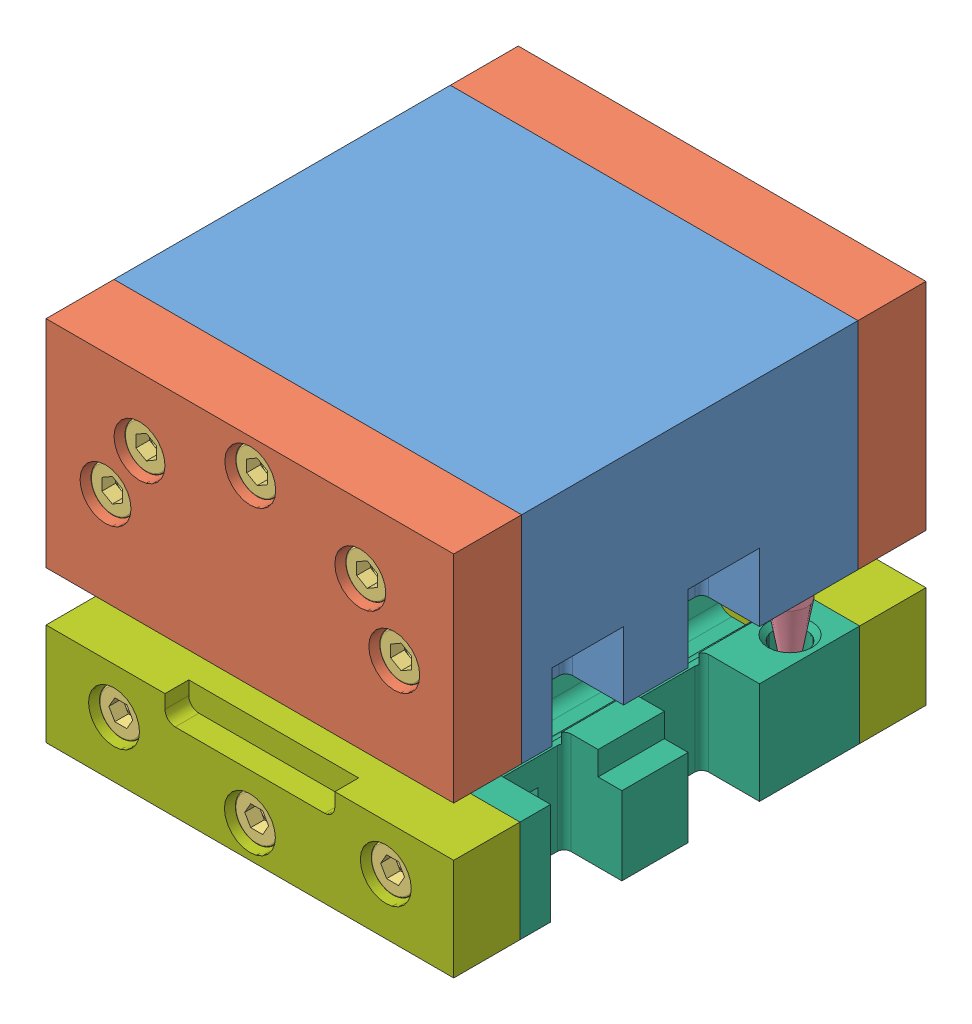
SolidWorks assembly Сборка, configuration По умолчанию. Lengths in mm.
Overall size (120 108.09 139).
27 component instances, 7 part files, 37 mates.
Components (placement in the parent):
- Матрица-1: Матрица [По умолчанию] at origin size (120 63.5 99)
- БоковинаПресс-формы-1: БоковинаПресс-формы [По умолчанию] at (0 63.5 0) x (0 0 -1) z (-1 0 0) size (20 63.5 120)
- БоковинаПресс-формы-2: БоковинаПресс-формы [По умолчанию] at (120 63.5 99) x (0 0 1) z (1 0 0) size (20 63.5 120)
- socket head cap screw_iso-1: socket head cap screw_iso [ISO 4762 M8 x 16 - 16N] at (17.5 27.5 117) x (0 0 -1) z (1 0 0) size (24 13 13)
- socket head cap screw_iso-2: socket head cap screw_iso [ISO 4762 M8 x 16 - 16N] at (27.5 43.5 117) x (0 0 -1) z (1 0 0) size (24 13 13)
- socket head cap screw_iso-3: socket head cap screw_iso [ISO 4762 M8 x 16 - 16N] at (60.109 53.5 117) x (0 0 -1) z (1 0 0) size (24 13 13)
- socket head cap screw_iso-4: socket head cap screw_iso [ISO 4762 M8 x 16 - 16N] at (92.5 43.5 117) x (0 0 -1) z (1 0 0) size (24 13 13)
- socket head cap screw_iso-5: socket head cap screw_iso [ISO 4762 M8 x 16 - 16N] at (102.5 27.5 117) x (0 0 -1) z (1 0 0) size (24 13 13)
- socket head cap screw_iso-6: socket head cap screw_iso [ISO 4762 M8 x 16 - 16N] at (102.5 27.5 -18) x (0 0 1) z (-1 0 0) size (24 13 13)
- socket head cap screw_iso-7: socket head cap screw_iso [ISO 4762 M8 x 16 - 16N] at (92.5 43.5 -18) x (0 0 1) z (-1 0 0) size (24 13 13)
- socket head cap screw_iso-8: socket head cap screw_iso [ISO 4762 M8 x 16 - 16N] at (59.891 53.5 -18) x (0 0 1) z (-1 0 0) size (24 13 13)
- socket head cap screw_iso-9: socket head cap screw_iso [ISO 4762 M8 x 16 - 16N] at (27.5 43.5 -18) x (0 0 1) z (-1 0 0) size (24 13 13)
- socket head cap screw_iso-10: socket head cap screw_iso [ISO 4762 M8 x 16 - 16N] at (17.5 27.5 -18) x (0 0 1) z (-1 0 0) size (24 13 13)
- Направляющая-2: Направляющая [По умолчанию] at (8 30 87) x (0 -1 0) z (0.779572 0 -0.626312) size (55 10 10)
- Направляющая-3: Направляющая [По умолчанию] at (112 30 12) x (0 -1 0) z (-0.854743 0 -0.519052) size (55 10 10)
- Подставка-1: Подставка [По умолчанию] at (60 33.5 76.5) x (0 -1 0) z (-0.902288 0 0.431134) size (36.5 13.89 13.89)
- Подставка-2: Подставка [По умолчанию] at (60 33.5 22.5) x (0 -1 0) z (-0.706159 0 0.708053) size (36.5 13.89 13.89)
- СборкаВерх-1: СборкаВерх [По умолчанию] at (0 -14.5929 99.5) x (1 0 0) z (0 1 0) size (120 139 30)
  - Пуансон-1: Пуансон [По умолчанию] at origin size (120 100 30)
  - БоковинаПуасона-1: БоковинаПуасона [По умолчанию] at (120 100 -30) x (-1 0 0) z (0 0 -1) size (120 19.5 30)
  - БоковинаПуасона-3: БоковинаПуасона [По умолчанию] at (0 0 -30) x (1 0 0) z (0 0 -1) size (120 19.5 30)
  - socket head cap screw_iso-1: socket head cap screw_iso [ISO 4762 M8 x 16 - 16N] at (100 -17.5 -13.5) x (0 1 0) z (0 0 1) size (24 13 13)
  - socket head cap screw_iso-2: socket head cap screw_iso [ISO 4762 M8 x 16 - 16N] at (60 -17.5 -20.5) x (0 1 0) z (0 0 1) size (24 13 13)
  - socket head cap screw_iso-3: socket head cap screw_iso [ISO 4762 M8 x 16 - 16N] at (20 -17.5 -13.5) x (0 1 0) z (0 0 1) size (24 13 13)
  - socket head cap screw_iso-4: socket head cap screw_iso [ISO 4762 M8 x 16 - 16N] at (20 117.5 -13.5) x (0 -1 0) z (0 0 1) size (24 13 13)
  - socket head cap screw_iso-5: socket head cap screw_iso [ISO 4762 M8 x 16 - 16N] at (60 117.5 -20.5) x (0 -1 0) z (0 0 1) size (24 13 13)
  - socket head cap screw_iso-6: socket head cap screw_iso [ISO 4762 M8 x 16 - 16N] at (100 117.5 -13.5) x (0 -1 0) z (0 0 1) size (24 13 13)
Mates (geometry in assembly coordinates):
- Совпадение1: coincident anti-aligned: plane of Матрица-1 through (0 0 0) normal (0 0 -1); plane of БоковинаПресс-формы-1 through (0 63.5 0) normal (0 0 1)
- Концентричный1: concentric aligned: cylinder of Матрица-1 through (92.5 43.5 30) axis (0 0 -1) radius 4; cylinder of БоковинаПресс-формы-1 through (92.5 43.5 0) axis (0 0 -1) radius 4.25
- Концентричный2: concentric aligned: cylinder of Матрица-1 through (27.5 43.5 30) axis (0 0 -1) radius 4; cylinder of БоковинаПресс-формы-1 through (27.5 43.5 0) axis (0 0 -1) radius 4.25
- Совпадение2: coincident anti-aligned: plane of Матрица-1 through (0 0 99) normal (0 0 1); plane of БоковинаПресс-формы-2 through (120 63.5 99) normal (0 0 -1)
- Концентричный4: concentric aligned: cylinder of Матрица-1 through (17.5 27.5 69) axis (0 0 1) radius 4; cylinder of БоковинаПресс-формы-2 through (17.5 27.5 99) axis (0 0 1) radius 4.25
- Концентричный5: concentric aligned: cylinder of Матрица-1 through (102.5 27.5 69) axis (0 0 1) radius 4; cylinder of БоковинаПресс-формы-2 through (102.5 27.5 99) axis (0 0 1) radius 4.25
- Концентричный6: concentric aligned: cylinder of БоковинаПресс-формы-2 through (17.5 27.5 99) axis (0 0 1) radius 4.25; cylinder of socket head cap screw_iso-1 through (17.5 27.5 148.75) axis (0 0 1) radius 6.5
- Совпадение3: coincident anti-aligned: plane of БоковинаПресс-формы-2 through (17.5 27.5 109) normal (0 0 1); plane of socket head cap screw_iso-1 through (17.5 34 109) normal (0 0 -1)
- Концентричный7: concentric aligned: cylinder of БоковинаПресс-формы-2 through (27.5 43.5 109) axis (0 0 1) radius 7.5; cylinder of socket head cap screw_iso-2 through (27.5 43.5 148.75) axis (0 0 1) radius 6.5
- Совпадение4: coincident anti-aligned: plane of БоковинаПресс-формы-2 through (27.5 43.5 109) normal (0 0 1); plane of socket head cap screw_iso-2 through (27.5 50 109) normal (0 0 -1)
- Концентричный8: concentric aligned: cylinder of БоковинаПресс-формы-2 through (60.109 53.5 99) axis (0 0 1) radius 4.25; cylinder of socket head cap screw_iso-3 through (60.109 53.5 148.75) axis (0 0 1) radius 6.5
- Совпадение5: coincident anti-aligned: plane of БоковинаПресс-формы-2 through (60.109 53.5 109) normal (0 0 1); plane of socket head cap screw_iso-3 through (60.109 60 109) normal (0 0 -1)
- Концентричный9: concentric aligned: cylinder of БоковинаПресс-формы-2 through (92.5 43.5 99) axis (0 0 1) radius 4.25; cylinder of socket head cap screw_iso-4 through (92.5 43.5 148.75) axis (0 0 1) radius 6.5
- Совпадение6: coincident anti-aligned: plane of БоковинаПресс-формы-2 through (92.5 43.5 109) normal (0 0 1); plane of socket head cap screw_iso-4 through (92.5 50 109) normal (0 0 -1)
- Концентричный10: concentric aligned: cylinder of БоковинаПресс-формы-2 through (102.5 27.5 99) axis (0 0 1) radius 4.25; cylinder of socket head cap screw_iso-5 through (102.5 27.5 148.75) axis (0 0 1) radius 6.5
- Совпадение7: coincident anti-aligned: plane of БоковинаПресс-формы-2 through (102.5 27.5 109) normal (0 0 1); plane of socket head cap screw_iso-5 through (102.5 34 109) normal (0 0 -1)
- Концентричный11: concentric aligned: cylinder of БоковинаПресс-формы-1 through (102.5 27.5 0) axis (0 0 -1) radius 4.25; cylinder of socket head cap screw_iso-6 through (102.5 27.5 -49.75) axis (0 0 -1) radius 6.5
- Совпадение8: coincident anti-aligned: plane of БоковинаПресс-формы-1 through (102.5 27.5 -10) normal (0 0 -1); plane of socket head cap screw_iso-6 through (102.5 34 -10) normal (0 0 1)
- Концентричный12: concentric aligned: cylinder of БоковинаПресс-формы-1 through (92.5 43.5 -10) axis (0 0 -1) radius 7.5; cylinder of socket head cap screw_iso-7 through (92.5 43.5 -49.75) axis (0 0 -1) radius 6.5
- Совпадение9: coincident anti-aligned: plane of БоковинаПресс-формы-1 through (92.5 43.5 -10) normal (0 0 -1); plane of socket head cap screw_iso-7 through (92.5 50 -10) normal (0 0 1)
- Концентричный13: concentric aligned: cylinder of БоковинаПресс-формы-1 through (59.891 53.5 0) axis (0 0 -1) radius 4.25; cylinder of socket head cap screw_iso-8 through (59.891 53.5 -49.75) axis (0 0 -1) radius 6.5
- Совпадение10: coincident anti-aligned: plane of БоковинаПресс-формы-1 through (59.891 53.5 -10) normal (0 0 -1); plane of socket head cap screw_iso-8 through (59.891 60 -10) normal (0 0 1)
- Концентричный14: concentric aligned: cylinder of БоковинаПресс-формы-1 through (27.5 43.5 0) axis (0 0 -1) radius 4.25; cylinder of socket head cap screw_iso-9 through (27.5 43.5 -49.75) axis (0 0 -1) radius 6.5
- Совпадение11: coincident anti-aligned: plane of БоковинаПресс-формы-1 through (27.5 43.5 -10) normal (0 0 -1); plane of socket head cap screw_iso-9 through (27.5 50 -10) normal (0 0 1)
- Концентричный15: concentric aligned: cylinder of БоковинаПресс-формы-1 through (17.5 27.5 -10) axis (0 0 -1) radius 7.5; cylinder of socket head cap screw_iso-10 through (17.5 27.5 -49.75) axis (0 0 -1) radius 6.5
- Совпадение12: coincident anti-aligned: plane of БоковинаПресс-формы-1 through (17.5 27.5 -10) normal (0 0 -1); plane of socket head cap screw_iso-10 through (17.5 34 -10) normal (0 0 1)
- Концентричный18: concentric anti-aligned: cylinder of Матрица-1 through (8 30 87) axis (0 -1 0) radius 5; cylinder of Направляющая-2 through (8 30 87) axis (0 1 0) radius 5
- Совпадение13: coincident anti-aligned: plane of Матрица-1 through (8 30 87) normal (0 -1 0); plane of Направляющая-2 through (8 30 87) normal (0 1 0)
- Концентричный19: concentric anti-aligned: cylinder of Матрица-1 through (112 30 12) axis (0 -1 0) radius 5; cylinder of Направляющая-3 through (112 30 12) axis (0 1 0) radius 5
- Совпадение14: coincident anti-aligned: plane of Матрица-1 through (112 30 12) normal (0 -1 0); plane of Направляющая-3 through (112 30 12) normal (0 1 0)
- Концентричный20: concentric anti-aligned: cylinder of Матрица-1 through (60 33.5 76.5) axis (0 -1 0) radius 6; cylinder of Подставка-1 through (60 33.5 76.5) axis (0 1 0) radius 6.9453
- Концентричный21: concentric anti-aligned: cylinder of Матрица-1 through (60 33.5 22.5) axis (0 -1 0) radius 6; cylinder of Подставка-2 through (60 33.5 22.5) axis (0 1 0) radius 6.9453
- Совпадение16: coincident anti-aligned: plane of Матрица-1 through (60 33.5 22.5) normal (0 -1 0); plane of Подставка-2 through (60 33.5 22.5) normal (0 1 0)
- Совпадение18: coincident aligned: plane of Подставка-1 through (63.6092 -3 74.7755) normal (0 -1 0); plane of Подставка-2 through (62.8246 -3 19.6678) normal (0 -1 0)
- Концентричный22: concentric aligned: cylinder of Направляющая-3 through (112 30 12) axis (0 1 0) radius 5; cylinder of СборкаВерх-1/Пуансон-1 through (112 -30 12) axis (0 1 0) radius 5
- Концентричный23: concentric aligned: cylinder of Направляющая-2 through (8 30 87) axis (0 1 0) radius 5; cylinder of СборкаВерх-1/Пуансон-1 through (8 -30 87) axis (0 1 0) radius 5
- Граничное расстояние1: limit distance = 14.5929 mm anti-aligned: plane of БоковинаПресс-формы-2 through (120 0 119) normal (0 -1 0); plane of СборкаВерх-1/БоковинаПуасона-3 through (0 -14.5929 119) normal (0 1 0)
